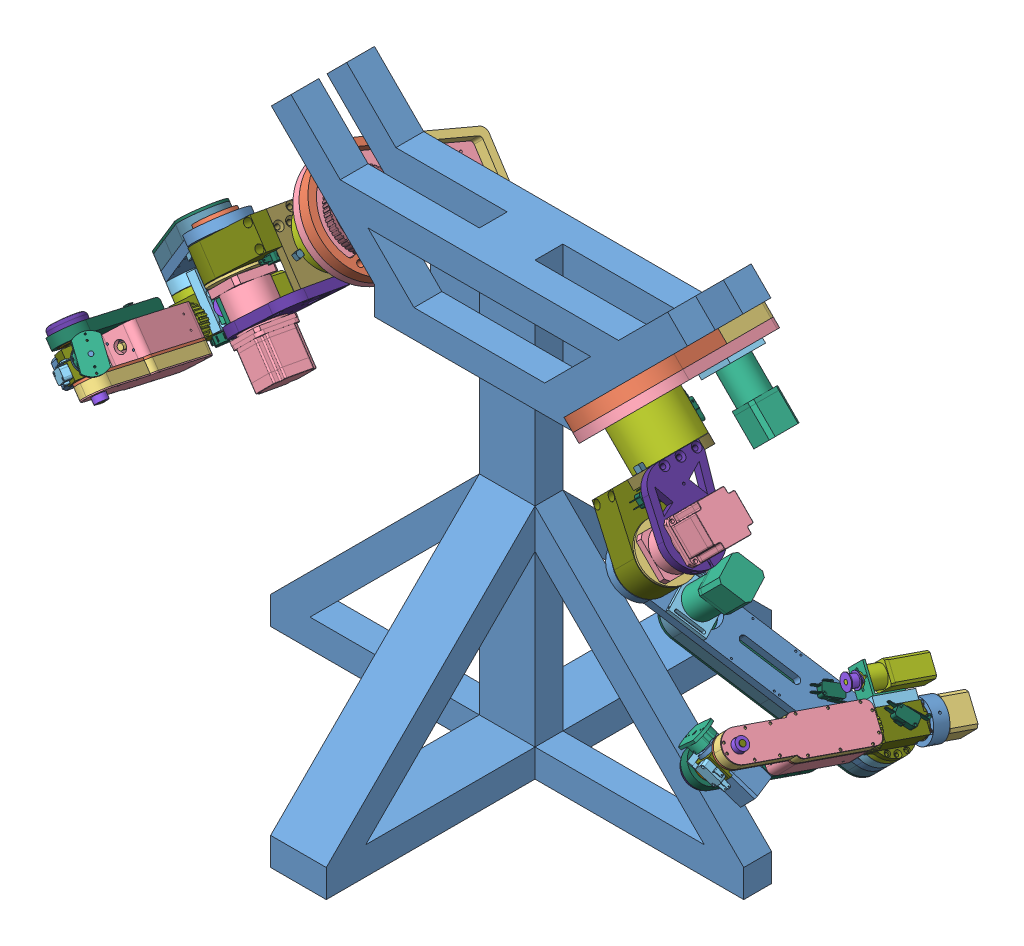
SolidWorks assembly AR2 Robot1, configuration 默认. Lengths in mm.
Overall size (1274.66 716.78 640).
167 component instances, 61 part files, 2 mates.
Components (placement in the parent):
- body_support2-1: body_support2 [默认] at (24.0266 -751.4877 1050.7107) size (680 716.78 640)
- AR2 Robot-1: AR2 Robot [Default] at (156.2197 -220.4156 1029.9878) x (0.706966 0.706966 0.01995) z (0.707107 -0.707107 0) size (202.33 345.86 499.96)
  - J1 base support spacer part 1-1: J1 base support spacer part 1 [Default] at (22.3846 43.8071 138.2023) size (150 163.98 18)
  - J1 base support spacer part 2-1: J1 base support spacer part 2 [Default] at (22.3846 43.8071 138.2023) size (115.01 90.53 18)
  - J1 Base Plate-1: J1 Base Plate [Default] at (22.3846 91.3071 156.2023) size (150 245 12.7)
  - J1 & J3 Motor Mount-1: J1 & J3 Motor Mount [Default] at (22.3846 -32.6929 168.9023) size (60 50 6.35)
  - 17HS15-1684S-HG50-1: 17HS15-1684S-HG50 [Default] at (22.3846 -32.6929 223.5523) size (42.3 42.3 112.8)
  - J1 Turret Housing-1: J1 Turret Housing [Default] at (22.3846 91.3071 224.9023) x (0 1 0) z (0 0 -1) size (88.9 88.9 60)
  - J1 timing drive pulley-1: J1 timing drive pulley [Default] at (22.3846 -32.6929 141.9013) x (0.998528 0.05424 0) z (0.05424 -0.998528 0) size (28 25 28)
  - J1 bearing outer-1: J1 bearing outer [Default] at (22.3846 91.3071 219.9023) x (0.366401 0.930457 0) z (-0.930457 0.366401 0) size (75 15.5 75)
  - J1 bearing outer-2: J1 bearing outer [Default] at (22.3846 91.3071 169.9023) x (0.999226 -0.039335 0) z (-0.039335 -0.999226 0) size (75 15.5 75)
  - J1 bearing inner-1: J1 bearing inner [Default] at (22.3846 91.3071 225.4756) x (0.21691 0.976192 0) z (-0.976192 0.21691 0) size (71.6 20 71.6)
  - J1 bearing inner-2: J1 bearing inner [Default] at (22.3846 91.3071 165.345) x (0.788003 0.615672 0) z (0.615672 -0.788003 0) size (71.6 20 71.6)
  - J1 Spindle-1: J1 Spindle [Default] at (22.3846 91.3071 230.4103) x (0.795489 -0.605968 0) z (0 0 -1) size (50 50 83)
  - J1 Turret Platform-1: J1 Turret Platform [Default] at (22.3846 91.3071 225.4103) x (0.999953 -0.00971 0) z (0 0 1) size (88.9 104.45 13.08)
  - J1 timing pulley-1: J1 timing pulley [Default] at (22.3846 91.3071 148.2513) x (0 0 1) z (0.134012 -0.99098 0) size (12.7 96.5 96.5)
  - 92635A314_SQUARE HEAD EXTENDED POINT SET SCREW-1: 92635A314_SQUARE HEAD EXTENDED POINT SET SCREW [92635A314] at (34.2576 140.3585 237.9103) x (-0.955272 0.295727 0) z (0 0 -1) size (8.33 8.21 30.75)
  - micro switch-1: micro switch [Valor predeterminado] at (22.4346 42.5829 198.1926) x (0 1 0) z (0 0 1) size (10.3 28.24 49.65)
  - J2 Turret Housing-1: J2 Turret Housing [Default] at (19.089 45.4301 436.03) x (0 0 1) z (-0.999953 0.00971 0) size (120.57 102.2 41.6)
  - J2 Motor Support-1: J2 Motor Support [Default] at (79.0823 44.4493 449.5798) x (0 0 1) z (-0.999953 0.00971 0) size (120.54 102.2 12.7)
  - 30206-1: 30206 [Default] at (11.5602 216.8333 260.6239) x (-0.009358 -0.96366 -0.266969) z (-0.002592 -0.266957 0.963705) size (65.5 17.98 65.5)
  - 30206-2: 30206 [Default] at (-12.4111 178.2286 233.8653) x (0.005755 0.592672 0.805423) z (-0.007821 -0.805385 0.5927) size (65.5 17.98 65.5)
  - J2 Arm-1: J2 Arm [Default] at (-22.7033 155.8935 307.9857) x (-0.008654 -0.89121 -0.453508) z (-0.999953 0.00971 0) size (76 373 12.7)
  - micro switch-2: micro switch [Valor predeterminado] at (-18.8536 37.4191 515.1548) x (0.999953 -0.00971 0) z (-0.008141 -0.838355 0.545065) size (10.3 28.24 49.65)
  - J2 Drive Spindle-1: J2 Drive Spindle [Default] at (20.1346 155.4775 307.9857) x (-0.008654 -0.89121 -0.453508) z (-0.999953 0.00971 0) size (50.8 50.8 61.54)
  - J2 Tension Ring-1: J2 Tension Ring [Default] at (21.0396 155.4687 307.9857) x (-0.009697 -0.998554 0.052877) z (0.999953 -0.00971 0) size (94.3 76 3.17)
  - micro switch-3: micro switch [Valor predeterminado] at (25.0171 140.9821 250.7197) x (0.999953 -0.00971 0) z (-0.00971 -0.999953 0) size (10.3 28.24 49.65)
  - 23HS22-2804S-HG50-1: 23HS22-2804S-HG50 [Default] at (82.6952 154.9259 307.9797) x (0.00971 0.999953 0) z (0 0 1) size (57 150.65 57)
  - J1 & J3 Motor Mount-2: J1 & J3 Motor Mount [Default] at (-23.0073 124.5927 369.5021) x (0.008654 0.89121 0.453508) z (0.999953 -0.00971 0) size (60 50 6.35)
  - 17HS15-1684S-HG50-2: 17HS15-1684S-HG50 [Default] at (31.6401 124.0621 369.5021) x (0.004404 0.453487 -0.891252) z (0.999953 -0.00971 0) size (42.3 42.3 112.8)
  - J3 Bearing Cup-1: J3 Bearing Cup [Default] at (-9.0472 17.4344 579.8176) x (0.008045 0.828458 0.559993) z (-0.999953 0.00971 0) size (60 60 15)
  - 30204 bearing-1: 30204 bearing [6677K54] at (-19.0467 17.5315 579.8176) x (0.003716 0.382666 -0.923879) z (0.999953 -0.00971 0) size (47 47 15.14)
  - J3 Spindle-1: J3 Spindle [Default] at (-9.0472 17.4344 579.8176) x (0.009307 0.958433 -0.285164) z (0.999953 -0.00971 0) size (60 60 50)
  - 5909K180_THRUST NEEDLE-ROLLER BRNG-1: 5909K180_THRUST NEEDLE-ROLLER BRNG [5909K18] at (-7.0473 17.415 579.8176) x (0.006928 0.713409 0.700713) z (-0.006804 -0.70068 0.713443) size (52 2 52)
  - 5909K630_THRUST NEEDLE-ROLLER BRNG-1: 5909K630_THRUST NEEDLE-ROLLER BRNG [5909K63] at (28.0358 56.6986 568.0293) x (-0.009307 -0.958433 0.285164) z (0.303367 0.26903 0.914107) size (3.2 39.69 39.69)
  - 5909K780_THRUST NEEDLE-ROLLER BRNG-1: 5909K780_THRUST NEEDLE-ROLLER BRNG [5909K78] at (-9.0472 17.4344 579.8176) x (0.999953 -0.00971 0) z (0.000045 0.004685 0.999989) size (1 52 52)
  - 5909K780_THRUST NEEDLE-ROLLER BRNG-2: 5909K780_THRUST NEEDLE-ROLLER BRNG [5909K78] at (-6.0473 17.4053 579.8176) x (0.999953 -0.00971 0) z (0.000043 0.004399 0.99999) size (1 52 52)
  - J3 spindle retainer-1: J3 spindle retainer [Default] at (-26.522 -31.3786 761.9544) x (0.002769 0.285151 0.958479) z (-0.999953 0.00971 0) size (31.75 31.75 2)
  - 5909K490_THRUST NEEDLE-ROLLER BRNG-1: 5909K490_THRUST NEEDLE-ROLLER BRNG [5909K49] at (27.4067 -8.0864 587.3049) x (-0.009307 -0.958433 0.285164) z (0.172118 0.279385 0.944627) size (0.81 39.69 39.69)
  - 1439K211_METRIC FULLY KEYED STEEL DRIVE SHAFT-1: 1439K211_METRIC FULLY KEYED STEEL DRIVE SHAFT [1439K211] at (-16.5468 17.5072 579.8176) x (-0.009307 -0.958433 0.285164) z (-0.999953 0.00971 0) size (8 7.87 35)
  - J2 arm cover spacer-1: J2 arm cover spacer [Default] at (-37.1017 -18.9384 323.0929) x (-0.008654 -0.89121 -0.453508) z (-0.999953 0.00971 0) size (60 145.49 19.05)
  - J2 arm cover spacer-2: J2 arm cover spacer [Default] at (-35.3729 159.0904 630.6831) x (0.008654 0.89121 0.453508) z (-0.999953 0.00971 0) size (60 145.49 19.05)
  - J2 side cover half -1: J2 side cover half  [Default] at (-58.4278 73.736 415.9133) x (0.008654 0.89121 0.453508) z (0.999953 -0.00971 0) size (60 162.81 3.17)
  - J2 side cover half -2: J2 side cover half  [Default] at (-58.4947 66.8476 537.8627) x (-0.008654 -0.89121 -0.453508) z (0.999953 -0.00971 0) size (60 162.81 3.17)
  - J4 Turret Housing-1: J4 Turret Housing [Default] at (0.9524 17.3373 579.8176) x (0.009307 0.958433 -0.285164) z (0.999953 -0.00971 0) size (58.8 60 45.4)
  - 5905K137_STL NEEDLE-ROLLER BRNG-2: 5905K137_STL NEEDLE-ROLLER BRNG [5905K137] at (27.8618 38.7782 573.3611) x (0.254471 0.273518 0.927595) z (-0.009307 -0.958433 0.285164) size (31.75 31.75 25.4)
  - J4 Main Shaft-1: J4 Main Shaft [Default] at (28.355 89.5657 558.2503) x (-0.999873 0.012613 0.009759) z (-0.009307 -0.958433 0.285164) size (25.4 25.4 116.3)
  - 5905K137_STL NEEDLE-ROLLER BRNG-1: 5905K137_STL NEEDLE-ROLLER BRNG [5905K137] at (27.551 6.7666 582.8856) x (0.991141 -0.046627 -0.124363) z (0.009307 0.958433 -0.285164) size (31.75 31.75 25.4)
  - J5 motor mount-1: J5 motor mount [Default] at (27.4308 -5.6068 586.5671) x (-0.999873 0.012613 0.009759) z (-0.009307 -0.958433 0.285164) size (52 52 20)
  - 5909K490_THRUST NEEDLE-ROLLER BRNG-2: 5909K490_THRUST NEEDLE-ROLLER BRNG [5909K49] at (27.4252 -6.1846 586.739) x (0.009307 0.958433 -0.285164) z (-0.878097 0.144266 0.456215) size (0.81 39.69 39.69)
  - 5909K360_THRUST NEEDLE-ROLLER BRNG-1: 5909K360_THRUST NEEDLE-ROLLER BRNG [5909K36] at (27.416 -7.1355 587.0219) x (0.437217 0.252572 0.863162) z (-0.899308 0.132712 0.416692) size (39.69 1.98 39.69)
  - 5909K490_THRUST NEEDLE-ROLLER BRNG-3: 5909K490_THRUST NEEDLE-ROLLER BRNG [5909K49] at (27.9876 51.7294 569.5078) x (-0.009307 -0.958433 0.285164) z (-0.202783 0.28106 0.938021) size (0.81 39.69 39.69)
  - 5909K360_THRUST NEEDLE-ROLLER BRNG-2: 5909K360_THRUST NEEDLE-ROLLER BRNG [5909K36] at (27.9968 52.6803 569.2248) x (0.998571 -0.023915 -0.047786) z (0.05262 0.284312 0.957287) size (39.69 1.98 39.69)
  - 17LS13-0404E-200H-1: 17LS13-0404E-200H [Default] at (26.9282 -57.3622 601.966) x (0.999873 -0.012613 -0.009759) z (0.009307 0.958433 -0.285164) size (42.3 42.3 236)
  - micro switch-4: micro switch [Valor predeterminado] at (51.3984 21.8369 575.1379) x (-0.999953 0.00971 0) z (-0.005226 -0.538152 0.842831) size (10.3 28.24 49.65)
  - J5 Housing-1: J5 Housing [Default] at (8.4486 72.983 589.5353) x (0.009307 0.958433 -0.285164) z (0.999873 -0.012613 -0.009759) size (107.7 50 40)
  - J4 motor mount - limit arm-1: J4 motor mount - limit arm [Default] at (46.5936 41.9599 540.1302) x (-0.999953 0.00971 0) z (-0.009307 -0.958433 0.285164) size (68 12.19 53.8)
  - nema 11 bracket-1: nema 11 bracket [Default] at (41.5482 37.3098 541.5282) x (-0.009307 -0.958433 0.285164) z (-0.999953 0.00971 0) size (40 40 30)
  - 11HS20-0674S-PG5-1: 11HS20-0674S-PG5 [Default] at (26.2041 1.9466 528.076) x (0.999953 -0.00971 0) z (-0.009307 -0.958433 0.285164) size (30.3 30.3 98.7)
  - J4 timing drive pulley-1: J4 timing drive pulley [Default] at (26.648 47.6639 514.4737) x (-0.165849 0.282707 0.94476) z (0.986107 0.038501 0.161586) size (21 20 21)
  - 6677K520_STL TAPERED-ROLLER BRNG-1: 6677K520_STL TAPERED-ROLLER BRNG [6677K52] at (4.2264 230.777 516.58) x (-0.013651 -0.993291 -0.114832) z (-0.999873 0.012613 0.009759) size (40 40 13.16)
  - 3mm rod-1: 3mm rod [Default] at (20.3071 172.9321 548.173) x (0.898948 -0.13292 -0.417403) z (-0.009307 -0.958433 0.285164) size (3 3 105)
  - 3mm rod-2: 3mm rod [Default] at (36.965 64.0885 551.1036) x (0.443693 0.251608 0.860133) z (0.009307 0.958433 -0.285164) size (3 3 105)
  - J5 Belt Carrier-1: J5 Belt Carrier [Default] at (38.5014 118.2441 548.7149) x (-0.995382 0.036126 0.088932) z (0.009307 0.958433 -0.285164) size (50.4 38.49 20.9)
  - J5 Belt Carrier Clamp-1: J5 Belt Carrier Clamp [Default] at (38.3643 129.2512 515.5701) x (-0.997523 -0.010986 -0.069481) z (-0.009307 -0.958433 0.285164) size (15.26 4.44 10)
  - J5 Idler Tension Block-1: J5 Idler Tension Block [Default] at (43.0941 83.6757 538.9353) x (-0.009307 -0.958433 0.285164) z (0.999873 -0.012613 -0.009759) size (15 40 5)
  - J5 Bearing Post-1: J5 Bearing Post [Default] at (48.2827 82.1251 560.1938) x (0.015948 0.791024 0.611577) z (0.999873 -0.012613 -0.009759) size (18.92 18.92 16.94)
  - J6 main bearing arm-1: J6 main bearing arm [Default] at (-5.1029 119.1644 575.984) x (0.009307 0.958433 -0.285164) z (0.999873 -0.012613 -0.009759) size (150 50 14)
  - micro switch-5: micro switch [Valor predeterminado] at (0.4979 134.3321 545.4175) x (0.01295 0.285037 0.958429) z (0.009307 0.958433 -0.285164) size (10.3 28.24 49.65)
  - J6 housing single piece-1: J6 housing single piece [Default] at (48.8777 191.7396 542.6928) x (-0.999873 0.012613 0.009759) z (-0.005075 0.328473 -0.9445) size (83.08 41 30.8)
  - J6 bearing cap-1: J6 bearing cap [Default] at (-4.4701 230.8867 516.6648) x (0.015119 0.555024 0.831697) z (-0.999873 0.012613 0.009759) size (46 46 10)
  - 5909K360_THRUST NEEDLE-ROLLER BRNG-3: 5909K360_THRUST NEEDLE-ROLLER BRNG [5909K36] at (-6.0773 230.907 516.6805) x (0.000889 0.655076 -0.755563) z (0.015923 0.755458 0.655003) size (39.69 1.98 39.69)
  - 5909K490_THRUST NEEDLE-ROLLER BRNG-4: 5909K490_THRUST NEEDLE-ROLLER BRNG [5909K49] at (-5.0852 230.8945 516.6709) x (0.999873 -0.012613 -0.009759) z (0.015948 0.792537 0.609615) size (0.81 39.69 39.69)
  - 5909K630_THRUST NEEDLE-ROLLER BRNG-2: 5909K630_THRUST NEEDLE-ROLLER BRNG [5909K63] at (-10.2693 230.9599 516.7215) x (0.999873 -0.012613 -0.009759) z (0.008673 -0.083448 0.996474) size (3.2 39.69 39.69)
  - J1 timing drive pulley-2: J1 timing drive pulley [Default] at (52.7144 230.1653 516.1067) x (0.004223 -0.380663 0.924704) z (0.015378 0.924628 0.380561) size (28 25 28)
  - 5905K760_STL NEEDLE-ROLLER BRNG-1: 5905K760_STL NEEDLE-ROLLER BRNG [5905K76] at (57.6485 82.007 560.1024) x (0.010168 0.032823 0.999409) z (-0.999873 0.012613 0.009759) size (22 22 12)
  - 14HS13-0804S-PG19-1: 14HS13-0804S-PG19 [Default] at (31.57 213.3877 565.3352) x (-0.015119 -0.944429 -0.328367) z (-0.005075 0.328473 -0.9445) size (35 35 87.8)
  - J5 side cover-1: J5 side cover [Default] at (50.0578 -32.289 564.6055) x (-0.003228 -0.759342 0.650684) z (-0.999873 0.012613 0.009759) size (184.01 109.77 3.17)
  - J5 side cover spacer-1: J5 side cover spacer [Default] at (65.0559 -32.4782 564.4591) x (-0.003228 -0.759342 0.650684) z (-0.999873 0.012613 0.009759) size (182.25 90.14 15)
  - J5 side cover spacer-2: J5 side cover spacer [Default] at (50.7924 -16.1211 618.9696) x (-0.013773 -0.991449 -0.129769) z (0.999873 -0.012613 -0.009759) size (182.25 90.14 15)
  - J5 side cover cap-1: J5 side cover cap [Default] at (67.2958 26.4304 555.1422) x (-0.003228 -0.759342 0.650684) z (-0.999873 0.012613 0.009759) size (184.01 109.77 1.59)
  - modified micro switch-1: modified micro switch [Valor predeterminado] at (37.2465 254.1199 525.5794) x (-0.015119 -0.944429 -0.328367) z (-0.005075 0.328473 -0.9445) size (18.14 22.93 48.86)
  - J6 gripper mount-1: J6 gripper mount [Default] at (31.2038 237.087 497.1895) x (0.992264 0.118813 0.035989) z (-0.005075 0.328473 -0.9445) size (48 32 16)
  - J4 timing hub-2: J4 timing hub [Default] at (27.9799 50.9408 569.7424) x (0.01295 0.285037 0.958429) z (0.009307 0.958433 -0.285164) size (44.7 44.7 15)
- AR2 Robot-2: AR2 Robot [Default] at (-43.8993 -204.6828 991.8925) x (0.699093 -0.699093 0.150129) z (-0.707107 -0.707107 0) size (202.33 345.86 499.96)
  - J1 base support spacer part 1-1: J1 base support spacer part 1 [Default] at (22.3846 43.8071 138.2023) size (150 163.98 18)
  - J1 base support spacer part 2-1: J1 base support spacer part 2 [Default] at (22.3846 43.8071 138.2023) size (115.01 90.53 18)
  - J1 Base Plate-1: J1 Base Plate [Default] at (22.3846 91.3071 156.2023) size (150 245 12.7)
  - J1 & J3 Motor Mount-1: J1 & J3 Motor Mount [Default] at (22.3846 -32.6929 168.9023) size (60 50 6.35)
  - 17HS15-1684S-HG50-1: 17HS15-1684S-HG50 [Default] at (22.3846 -32.6929 223.5523) size (42.3 42.3 112.8)
  - J1 Turret Housing-1: J1 Turret Housing [Default] at (22.3846 91.3071 224.9023) x (0 1 0) z (0 0 -1) size (88.9 88.9 60)
  - J1 timing drive pulley-1: J1 timing drive pulley [Default] at (22.3846 -32.6929 141.9013) x (0.998528 0.05424 0) z (0.05424 -0.998528 0) size (28 25 28)
  - J1 bearing outer-1: J1 bearing outer [Default] at (22.3846 91.3071 219.9023) x (0.366401 0.930457 0) z (-0.930457 0.366401 0) size (75 15.5 75)
  - J1 bearing outer-2: J1 bearing outer [Default] at (22.3846 91.3071 169.9023) x (0.999226 -0.039335 0) z (-0.039335 -0.999226 0) size (75 15.5 75)
  - J1 bearing inner-1: J1 bearing inner [Default] at (22.3846 91.3071 225.4756) x (0.21691 0.976192 0) z (-0.976192 0.21691 0) size (71.6 20 71.6)
  - J1 bearing inner-2: J1 bearing inner [Default] at (22.3846 91.3071 165.345) x (0.788003 0.615672 0) z (0.615672 -0.788003 0) size (71.6 20 71.6)
  - J1 Spindle-1: J1 Spindle [Default] at (22.3846 91.3071 230.4103) x (0.795489 -0.605968 0) z (0 0 -1) size (50 50 83)
  - J1 Turret Platform-1: J1 Turret Platform [Default] at (22.3846 91.3071 225.4103) x (0.999953 -0.00971 0) z (0 0 1) size (88.9 104.45 13.08)
  - J1 timing pulley-1: J1 timing pulley [Default] at (22.3846 91.3071 148.2513) x (0 0 1) z (0.134012 -0.99098 0) size (12.7 96.5 96.5)
  - 92635A314_SQUARE HEAD EXTENDED POINT SET SCREW-1: 92635A314_SQUARE HEAD EXTENDED POINT SET SCREW [92635A314] at (34.2576 140.3585 237.9103) x (-0.955272 0.295727 0) z (0 0 -1) size (8.33 8.21 30.75)
  - micro switch-1: micro switch [Valor predeterminado] at (22.4346 42.5829 198.1926) x (0 1 0) z (0 0 1) size (10.3 28.24 49.65)
  - J2 Turret Housing-1: J2 Turret Housing [Default] at (19.089 45.4301 436.03) x (0 0 1) z (-0.999953 0.00971 0) size (120.57 102.2 41.6)
  - J2 Motor Support-1: J2 Motor Support [Default] at (79.0823 44.4493 449.5798) x (0 0 1) z (-0.999953 0.00971 0) size (120.54 102.2 12.7)
  - 30206-1: 30206 [Default] at (11.5602 216.8333 260.6239) x (-0.009358 -0.96366 -0.266969) z (-0.002592 -0.266957 0.963705) size (65.5 17.98 65.5)
  - 30206-2: 30206 [Default] at (-12.4111 178.2286 233.8653) x (0.005755 0.592672 0.805423) z (-0.007821 -0.805385 0.5927) size (65.5 17.98 65.5)
  - J2 Arm-1: J2 Arm [Default] at (-22.7033 155.8935 307.9857) x (-0.008654 -0.89121 -0.453508) z (-0.999953 0.00971 0) size (76 373 12.7)
  - micro switch-2: micro switch [Valor predeterminado] at (-18.8536 37.4191 515.1548) x (0.999953 -0.00971 0) z (-0.008141 -0.838355 0.545065) size (10.3 28.24 49.65)
  - J2 Drive Spindle-1: J2 Drive Spindle [Default] at (20.1346 155.4775 307.9857) x (-0.008654 -0.89121 -0.453508) z (-0.999953 0.00971 0) size (50.8 50.8 61.54)
  - J2 Tension Ring-1: J2 Tension Ring [Default] at (21.0396 155.4687 307.9857) x (-0.009697 -0.998554 0.052877) z (0.999953 -0.00971 0) size (94.3 76 3.17)
  - micro switch-3: micro switch [Valor predeterminado] at (25.0171 140.9821 250.7197) x (0.999953 -0.00971 0) z (-0.00971 -0.999953 0) size (10.3 28.24 49.65)
  - 23HS22-2804S-HG50-1: 23HS22-2804S-HG50 [Default] at (82.6952 154.9259 307.9797) x (0.00971 0.999953 0) z (0 0 1) size (57 150.65 57)
  - J1 & J3 Motor Mount-2: J1 & J3 Motor Mount [Default] at (-23.0073 124.5927 369.5021) x (0.008654 0.89121 0.453508) z (0.999953 -0.00971 0) size (60 50 6.35)
  - 17HS15-1684S-HG50-2: 17HS15-1684S-HG50 [Default] at (31.6401 124.0621 369.5021) x (0.004404 0.453487 -0.891252) z (0.999953 -0.00971 0) size (42.3 42.3 112.8)
  - J3 Bearing Cup-1: J3 Bearing Cup [Default] at (-9.0472 17.4344 579.8176) x (0.008045 0.828458 0.559993) z (-0.999953 0.00971 0) size (60 60 15)
  - 30204 bearing-1: 30204 bearing [6677K54] at (-19.0467 17.5315 579.8176) x (0.003716 0.382666 -0.923879) z (0.999953 -0.00971 0) size (47 47 15.14)
  - J3 Spindle-1: J3 Spindle [Default] at (-9.0472 17.4344 579.8176) x (0.009307 0.958433 -0.285164) z (0.999953 -0.00971 0) size (60 60 50)
  - 5909K180_THRUST NEEDLE-ROLLER BRNG-1: 5909K180_THRUST NEEDLE-ROLLER BRNG [5909K18] at (-7.0473 17.415 579.8176) x (0.006928 0.713409 0.700713) z (-0.006804 -0.70068 0.713443) size (52 2 52)
  - 5909K630_THRUST NEEDLE-ROLLER BRNG-1: 5909K630_THRUST NEEDLE-ROLLER BRNG [5909K63] at (28.0358 56.6986 568.0293) x (-0.009307 -0.958433 0.285164) z (0.303367 0.26903 0.914107) size (3.2 39.69 39.69)
  - 5909K780_THRUST NEEDLE-ROLLER BRNG-1: 5909K780_THRUST NEEDLE-ROLLER BRNG [5909K78] at (-9.0472 17.4344 579.8176) x (0.999953 -0.00971 0) z (0.000045 0.004685 0.999989) size (1 52 52)
  - 5909K780_THRUST NEEDLE-ROLLER BRNG-2: 5909K780_THRUST NEEDLE-ROLLER BRNG [5909K78] at (-6.0473 17.4053 579.8176) x (0.999953 -0.00971 0) z (0.000043 0.004399 0.99999) size (1 52 52)
  - J3 spindle retainer-1: J3 spindle retainer [Default] at (-26.522 -31.3786 761.9544) x (0.002769 0.285151 0.958479) z (-0.999953 0.00971 0) size (31.75 31.75 2)
  - 5909K490_THRUST NEEDLE-ROLLER BRNG-1: 5909K490_THRUST NEEDLE-ROLLER BRNG [5909K49] at (27.4067 -8.0864 587.3049) x (-0.009307 -0.958433 0.285164) z (0.172118 0.279385 0.944627) size (0.81 39.69 39.69)
  - 1439K211_METRIC FULLY KEYED STEEL DRIVE SHAFT-1: 1439K211_METRIC FULLY KEYED STEEL DRIVE SHAFT [1439K211] at (-16.5468 17.5072 579.8176) x (-0.009307 -0.958433 0.285164) z (-0.999953 0.00971 0) size (8 7.87 35)
  - J2 arm cover spacer-1: J2 arm cover spacer [Default] at (-37.1017 -18.9384 323.0929) x (-0.008654 -0.89121 -0.453508) z (-0.999953 0.00971 0) size (60 145.49 19.05)
  - J2 arm cover spacer-2: J2 arm cover spacer [Default] at (-35.3729 159.0904 630.6831) x (0.008654 0.89121 0.453508) z (-0.999953 0.00971 0) size (60 145.49 19.05)
  - J2 side cover half -1: J2 side cover half  [Default] at (-58.4278 73.736 415.9133) x (0.008654 0.89121 0.453508) z (0.999953 -0.00971 0) size (60 162.81 3.17)
  - J2 side cover half -2: J2 side cover half  [Default] at (-58.4947 66.8476 537.8627) x (-0.008654 -0.89121 -0.453508) z (0.999953 -0.00971 0) size (60 162.81 3.17)
  - J4 Turret Housing-1: J4 Turret Housing [Default] at (0.9524 17.3373 579.8176) x (0.009307 0.958433 -0.285164) z (0.999953 -0.00971 0) size (58.8 60 45.4)
  - 5905K137_STL NEEDLE-ROLLER BRNG-2: 5905K137_STL NEEDLE-ROLLER BRNG [5905K137] at (27.8618 38.7782 573.3611) x (0.254471 0.273518 0.927595) z (-0.009307 -0.958433 0.285164) size (31.75 31.75 25.4)
  - J4 Main Shaft-1: J4 Main Shaft [Default] at (28.355 89.5657 558.2503) x (-0.999873 0.012613 0.009759) z (-0.009307 -0.958433 0.285164) size (25.4 25.4 116.3)
  - 5905K137_STL NEEDLE-ROLLER BRNG-1: 5905K137_STL NEEDLE-ROLLER BRNG [5905K137] at (27.551 6.7666 582.8856) x (0.991141 -0.046627 -0.124363) z (0.009307 0.958433 -0.285164) size (31.75 31.75 25.4)
  - J5 motor mount-1: J5 motor mount [Default] at (27.4308 -5.6068 586.5671) x (-0.999873 0.012613 0.009759) z (-0.009307 -0.958433 0.285164) size (52 52 20)
  - 5909K490_THRUST NEEDLE-ROLLER BRNG-2: 5909K490_THRUST NEEDLE-ROLLER BRNG [5909K49] at (27.4252 -6.1846 586.739) x (0.009307 0.958433 -0.285164) z (-0.878097 0.144266 0.456215) size (0.81 39.69 39.69)
  - 5909K360_THRUST NEEDLE-ROLLER BRNG-1: 5909K360_THRUST NEEDLE-ROLLER BRNG [5909K36] at (27.416 -7.1355 587.0219) x (0.437217 0.252572 0.863162) z (-0.899308 0.132712 0.416692) size (39.69 1.98 39.69)
  - 5909K490_THRUST NEEDLE-ROLLER BRNG-3: 5909K490_THRUST NEEDLE-ROLLER BRNG [5909K49] at (27.9876 51.7294 569.5078) x (-0.009307 -0.958433 0.285164) z (-0.202783 0.28106 0.938021) size (0.81 39.69 39.69)
  - 5909K360_THRUST NEEDLE-ROLLER BRNG-2: 5909K360_THRUST NEEDLE-ROLLER BRNG [5909K36] at (27.9968 52.6803 569.2248) x (0.998571 -0.023915 -0.047786) z (0.05262 0.284312 0.957287) size (39.69 1.98 39.69)
  - 17LS13-0404E-200H-1: 17LS13-0404E-200H [Default] at (26.9282 -57.3622 601.966) x (0.999873 -0.012613 -0.009759) z (0.009307 0.958433 -0.285164) size (42.3 42.3 236)
  - micro switch-4: micro switch [Valor predeterminado] at (51.3984 21.8369 575.1379) x (-0.999953 0.00971 0) z (-0.005226 -0.538152 0.842831) size (10.3 28.24 49.65)
  - J5 Housing-1: J5 Housing [Default] at (8.4486 72.983 589.5353) x (0.009307 0.958433 -0.285164) z (0.999873 -0.012613 -0.009759) size (107.7 50 40)
  - J4 motor mount - limit arm-1: J4 motor mount - limit arm [Default] at (46.5936 41.9599 540.1302) x (-0.999953 0.00971 0) z (-0.009307 -0.958433 0.285164) size (68 12.19 53.8)
  - nema 11 bracket-1: nema 11 bracket [Default] at (41.5482 37.3098 541.5282) x (-0.009307 -0.958433 0.285164) z (-0.999953 0.00971 0) size (40 40 30)
  - 11HS20-0674S-PG5-1: 11HS20-0674S-PG5 [Default] at (26.2041 1.9466 528.076) x (0.999953 -0.00971 0) z (-0.009307 -0.958433 0.285164) size (30.3 30.3 98.7)
  - J4 timing drive pulley-1: J4 timing drive pulley [Default] at (26.648 47.6639 514.4737) x (-0.165849 0.282707 0.94476) z (0.986107 0.038501 0.161586) size (21 20 21)
  - 6677K520_STL TAPERED-ROLLER BRNG-1: 6677K520_STL TAPERED-ROLLER BRNG [6677K52] at (4.2264 230.777 516.58) x (-0.013651 -0.993291 -0.114832) z (-0.999873 0.012613 0.009759) size (40 40 13.16)
  - 3mm rod-1: 3mm rod [Default] at (20.3071 172.9321 548.173) x (0.898948 -0.13292 -0.417403) z (-0.009307 -0.958433 0.285164) size (3 3 105)
  - 3mm rod-2: 3mm rod [Default] at (36.965 64.0885 551.1036) x (0.443693 0.251608 0.860133) z (0.009307 0.958433 -0.285164) size (3 3 105)
  - J5 Belt Carrier-1: J5 Belt Carrier [Default] at (38.5014 118.2441 548.7149) x (-0.995382 0.036126 0.088932) z (0.009307 0.958433 -0.285164) size (50.4 38.49 20.9)
  - J5 Belt Carrier Clamp-1: J5 Belt Carrier Clamp [Default] at (38.3643 129.2512 515.5701) x (-0.997523 -0.010986 -0.069481) z (-0.009307 -0.958433 0.285164) size (15.26 4.44 10)
  - J5 Idler Tension Block-1: J5 Idler Tension Block [Default] at (43.0941 83.6757 538.9353) x (-0.009307 -0.958433 0.285164) z (0.999873 -0.012613 -0.009759) size (15 40 5)
  - J5 Bearing Post-1: J5 Bearing Post [Default] at (48.2827 82.1251 560.1938) x (0.015948 0.791024 0.611577) z (0.999873 -0.012613 -0.009759) size (18.92 18.92 16.94)
  - J6 main bearing arm-1: J6 main bearing arm [Default] at (-5.1029 119.1644 575.984) x (0.009307 0.958433 -0.285164) z (0.999873 -0.012613 -0.009759) size (150 50 14)
  - micro switch-5: micro switch [Valor predeterminado] at (0.4979 134.3321 545.4175) x (0.01295 0.285037 0.958429) z (0.009307 0.958433 -0.285164) size (10.3 28.24 49.65)
  - J6 housing single piece-1: J6 housing single piece [Default] at (48.8777 191.7396 542.6928) x (-0.999873 0.012613 0.009759) z (-0.005075 0.328473 -0.9445) size (83.08 41 30.8)
  - J6 bearing cap-1: J6 bearing cap [Default] at (-4.4701 230.8867 516.6648) x (0.015119 0.555024 0.831697) z (-0.999873 0.012613 0.009759) size (46 46 10)
  - 5909K360_THRUST NEEDLE-ROLLER BRNG-3: 5909K360_THRUST NEEDLE-ROLLER BRNG [5909K36] at (-6.0773 230.907 516.6805) x (0.000889 0.655076 -0.755563) z (0.015923 0.755458 0.655003) size (39.69 1.98 39.69)
  - 5909K490_THRUST NEEDLE-ROLLER BRNG-4: 5909K490_THRUST NEEDLE-ROLLER BRNG [5909K49] at (-5.0852 230.8945 516.6709) x (0.999873 -0.012613 -0.009759) z (0.015948 0.792537 0.609615) size (0.81 39.69 39.69)
  - 5909K630_THRUST NEEDLE-ROLLER BRNG-2: 5909K630_THRUST NEEDLE-ROLLER BRNG [5909K63] at (-10.2693 230.9599 516.7215) x (0.999873 -0.012613 -0.009759) z (0.008673 -0.083448 0.996474) size (3.2 39.69 39.69)
  - J1 timing drive pulley-2: J1 timing drive pulley [Default] at (52.7144 230.1653 516.1067) x (0.004223 -0.380663 0.924704) z (0.015378 0.924628 0.380561) size (28 25 28)
  - 5905K760_STL NEEDLE-ROLLER BRNG-1: 5905K760_STL NEEDLE-ROLLER BRNG [5905K76] at (57.6485 82.007 560.1024) x (0.010168 0.032823 0.999409) z (-0.999873 0.012613 0.009759) size (22 22 12)
  - 14HS13-0804S-PG19-1: 14HS13-0804S-PG19 [Default] at (31.57 213.3877 565.3352) x (-0.015119 -0.944429 -0.328367) z (-0.005075 0.328473 -0.9445) size (35 35 87.8)
  - J5 side cover-1: J5 side cover [Default] at (50.0578 -32.289 564.6055) x (-0.003228 -0.759342 0.650684) z (-0.999873 0.012613 0.009759) size (184.01 109.77 3.17)
  - J5 side cover spacer-1: J5 side cover spacer [Default] at (65.0559 -32.4782 564.4591) x (-0.003228 -0.759342 0.650684) z (-0.999873 0.012613 0.009759) size (182.25 90.14 15)
  - J5 side cover spacer-2: J5 side cover spacer [Default] at (50.7924 -16.1211 618.9696) x (-0.013773 -0.991449 -0.129769) z (0.999873 -0.012613 -0.009759) size (182.25 90.14 15)
  - J5 side cover cap-1: J5 side cover cap [Default] at (67.2958 26.4304 555.1422) x (-0.003228 -0.759342 0.650684) z (-0.999873 0.012613 0.009759) size (184.01 109.77 1.59)
  - modified micro switch-1: modified micro switch [Valor predeterminado] at (37.2465 254.1199 525.5794) x (-0.015119 -0.944429 -0.328367) z (-0.005075 0.328473 -0.9445) size (18.14 22.93 48.86)
  - J6 gripper mount-1: J6 gripper mount [Default] at (31.2038 237.087 497.1895) x (0.992264 0.118813 0.035989) z (-0.005075 0.328473 -0.9445) size (48 32 16)
  - J4 timing hub-2: J4 timing hub [Default] at (27.9799 50.9408 569.7424) x (0.01295 0.285037 0.958429) z (0.009307 0.958433 -0.285164) size (44.7 44.7 15)
Mates (geometry in assembly coordinates):
- 重合1: coincident anti-aligned: plane of body_support2-1 through (-77.6891 -649.772 1050.7107) normal (0.707107 -0.707107 0); plane of AR2 Robot-1/J1 base support spacer part 1-1 through (248.1644 -323.9185 961.1181) normal (-0.707107 0.707107 0)
- 重合2: coincident anti-aligned: plane of body_support2-1 through (165.7423 -609.772 1050.7107) normal (-0.707107 -0.707107 0); plane of AR2 Robot-2/J1 base support spacer part 1-1 through (-141.0038 -303.0258 922.5451) normal (0.707107 0.707107 0)
